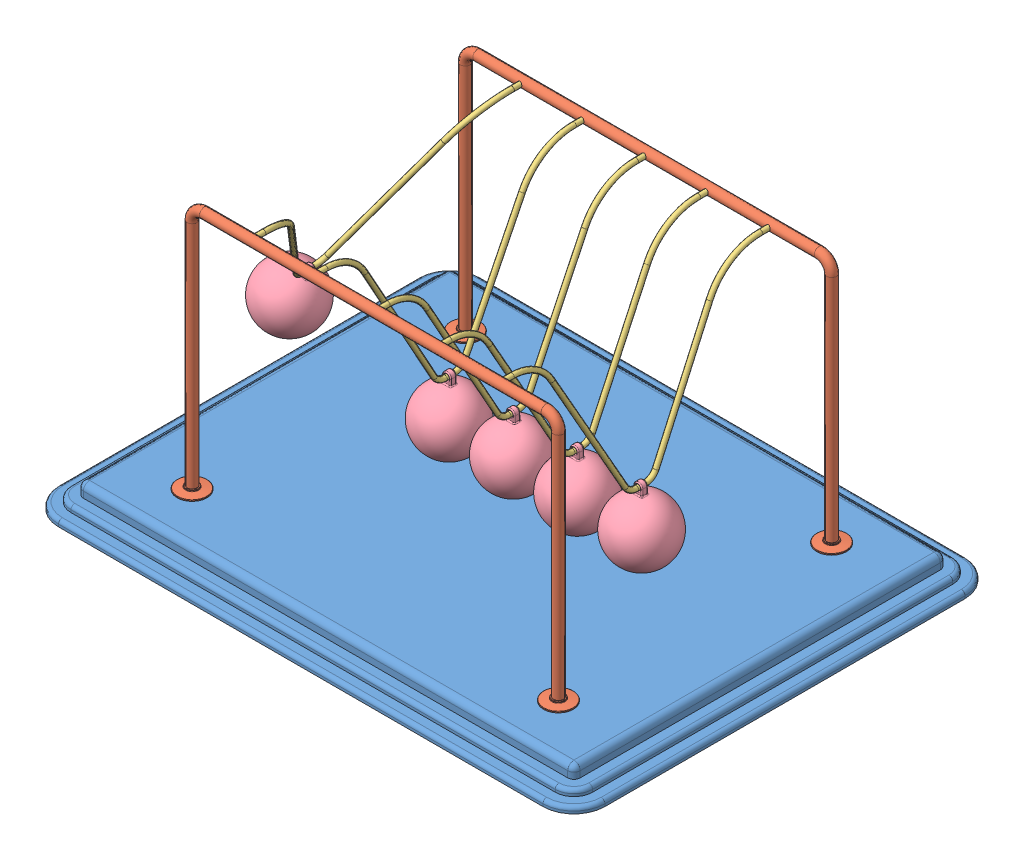
SolidWorks assembly Newtons Cradle NewtonsCradle 0243, configuration Default. Lengths in mm.
Overall size (440 222 340).
13 component instances, 4 part files, 34 mates.
Components (placement in the parent):
- Base NewtonsCradle 0243-1: Base NewtonsCradle 0243 [Default] at (-16.2968 -4.1587 11.425) size (440 20 340)
- frame NewtonsCradle 0243-1: frame NewtonsCradle 0243 [Default] at (-16.2968 144.4547 -98.575) size (319 202 24)
- frame NewtonsCradle 0243-2: frame NewtonsCradle 0243 [Default] at (-16.2968 144.4547 121.425) x (-1 0 0) z (0 0 -1) size (319 202 24)
- Hanging thing NewtonsCradle 0243-1: Hanging thing NewtonsCradle 0243 [Default] at (-157.6326 134.1825 11.425) x (0 0 1) z (-0.859985 0.510319 0) size (220 129 4)
- Hanging thing NewtonsCradle 0243-2: Hanging thing NewtonsCradle 0243 [Default] at (-66.576 122.8418 11.425) x (0 0 1) z (-0.999994 0.003446 0) size (220 129 4)
- Hanging thing NewtonsCradle 0243-3: Hanging thing NewtonsCradle 0243 [Default] at (-15.6923 122.8436 11.425) x (0 0 1) z (-0.999972 -0.007464 0) size (220 129 4)
- Hanging thing NewtonsCradle 0243-4: Hanging thing NewtonsCradle 0243 [Default] at (35.2213 122.8555 11.425) x (0 0 1) z (-0.999824 -0.018742 0) size (220 129 4)
- Hanging thing NewtonsCradle 0243-5: Hanging thing NewtonsCradle 0243 [Default] at (86.0287 122.8747 11.425) x (0 0 1) z (-0.999588 -0.028711 0) size (220 129 4)
- Sphere NewtonsCradle 0243-1: Sphere NewtonsCradle 0243 [Default] at (-195.3962 70.5436 11.425) x (0.859985 -0.510319 0) z (0 0 1) size (50 58.5 50)
- Sphere NewtonsCradle 0243-2: Sphere NewtonsCradle 0243 [Default] at (88.1533 48.9052 11.425) x (0.999588 0.028711 0) z (0 0 1) size (50 58.5 50)
- Sphere NewtonsCradle 0243-3: Sphere NewtonsCradle 0243 [Default] at (-15.14 48.8456 11.425) x (0.999972 0.007464 0) z (0 0 1) size (50 58.5 50)
- Sphere NewtonsCradle 0243-4: Sphere NewtonsCradle 0243 [Default] at (36.6081 48.8685 11.425) x (0.999824 0.018742 0) z (0 0 1) size (50 58.5 50)
- Sphere NewtonsCradle 0243-5: Sphere NewtonsCradle 0243 [Default] at (-66.831 48.8422 11.425) x (0.999994 -0.003446 0) z (0 0 1) size (50 58.5 50)
Mates (geometry in assembly coordinates):
- Coincident1: coincident anti-aligned: plane of Base-1 through (-211.2968 5.8413 156.425) normal (0 1 0); plane of frame-2 through (-175.7968 5.8413 121.425) normal (0 -1 0)
- Coincident2: coincident anti-aligned: plane of Base-1 through (-211.2968 5.8413 156.425) normal (0 1 0); plane of frame-1 through (143.2032 5.8413 -98.575) normal (0 -1 0)
- Concentric1: concentric anti-aligned: cylinder of frame-1 through (-116.2968 203.8413 -94.575) axis (0 0 -1) radius 2; cylinder of frame-2 through (-116.2968 203.8413 117.425) axis (0 0 1) radius 2
- Concentric2: concentric anti-aligned: cylinder of frame-1 through (83.7032 203.8413 -94.575) axis (0 0 -1) radius 2; cylinder of frame-2 through (83.7032 203.8413 117.425) axis (0 0 1) radius 2
- Distance1: distance = 60 mm: plane of frame-1 through (-16.2968 144.4547 -98.575) normal (0 0 1); line of Base-1 through (-211.2968 -12.1587 -158.575) axis (1 0 0)
- Distance2: distance = 60 mm: line of Base-1 through (178.7032 -12.1587 181.425) axis (-1 0 0); plane of frame-2 through (-16.2968 144.4547 121.425) normal (0 0 -1)
- Distance3: distance = 220 mm: plane of frame-2 through (-16.2968 144.4547 121.425) normal (-1 0 0); line of Base-1 through (-236.2968 -12.1587 156.425) axis (0 0 -1)
- Concentric3: concentric anti-aligned: cylinder of frame-1 through (-116.2968 203.8413 -94.575) axis (0 0 -1) radius 2; cylinder of Hanging thing-1 through (-116.2968 203.8413 111.425) axis (0 0 1) radius 2
- Concentric4: concentric anti-aligned: cylinder of frame-1 through (-116.2968 203.8413 -94.575) axis (0 0 -1) radius 2; cylinder of Hanging thing-1 through (-116.2968 203.8413 -98.575) axis (0 0 1) radius 2
- Concentric5: concentric aligned: cylinder of frame-2 through (-66.2968 203.8413 117.425) axis (0 0 1) radius 2; cylinder of Hanging thing-2 through (-66.2968 203.8413 111.425) axis (0 0 1) radius 2
- Concentric6: concentric aligned: cylinder of frame-2 through (-16.2968 203.8413 117.425) axis (0 0 1) radius 2; cylinder of Hanging thing-3 through (-16.2968 203.8413 111.425) axis (0 0 1) radius 2
- Concentric7: concentric aligned: cylinder of frame-2 through (33.7032 203.8413 117.425) axis (0 0 1) radius 2; cylinder of Hanging thing-4 through (33.7032 203.8413 111.425) axis (0 0 1) radius 2
- Concentric8: concentric aligned: cylinder of frame-2 through (83.7032 203.8413 117.425) axis (0 0 1) radius 2; cylinder of Hanging thing-5 through (83.7032 203.8413 111.425) axis (0 0 1) radius 2
- Coincident5: coincident anti-aligned: plane of frame-2 through (83.7032 203.8413 121.425) normal (0 0 -1); plane of Hanging thing-5 through (83.7032 203.8413 121.425) normal (0 0 1)
- Coincident6: coincident anti-aligned: plane of frame-2 through (33.7032 203.8413 121.425) normal (0 0 -1); plane of Hanging thing-4 through (33.7032 203.8413 121.425) normal (0 0 1)
- Coincident7: coincident anti-aligned: plane of frame-2 through (-16.2968 203.8413 121.425) normal (0 0 -1); plane of Hanging thing-3 through (-16.2968 203.8413 121.425) normal (0 0 1)
- Coincident8: coincident anti-aligned: plane of frame-2 through (-66.2968 203.8413 121.425) normal (0 0 -1); plane of Hanging thing-2 through (-66.2968 203.8413 121.425) normal (0 0 1)
- Coincident9: coincident anti-aligned: plane of frame-2 through (-116.2968 203.8413 121.425) normal (0 0 -1); plane of Hanging thing-1 through (-116.2968 203.8413 121.425) normal (0 0 1)
- Concentric9: concentric anti-aligned: cylinder of Hanging thing-1 through (-117.0163 78.8434 7.925) axis (0 0 1) radius 2; cylinder of Sphere-1 through (-117.0163 78.8434 13.925) axis (0 0 -1) radius 2
- Concentric13: concentric anti-aligned: cylinder of Hanging thing-2 through (-66.7276 78.842 7.925) axis (0 0 1) radius 2; cylinder of Sphere-5 through (-66.7276 78.842 13.925) axis (0 0 -1) radius 2
- Concentric15: concentric anti-aligned: cylinder of Hanging thing-3 through (-15.3639 78.8448 7.925) axis (0 0 1) radius 2; cylinder of Sphere-3 through (-15.3639 78.8448 13.925) axis (0 0 -1) radius 2
- Concentric16: concentric anti-aligned: cylinder of Hanging thing-5 through (87.292 78.8928 7.925) axis (0 0 1) radius 2; cylinder of Sphere-2 through (87.292 78.8928 13.925) axis (0 0 -1) radius 2
- Concentric17: concentric anti-aligned: cylinder of Hanging thing-4 through (36.0459 78.8632 7.925) axis (0 0 1) radius 2; cylinder of Sphere-4 through (36.0459 78.8632 13.925) axis (0 0 -1) radius 2
- Parallel1: parallel anti-aligned: plane of Hanging thing-1; plane of Sphere-1
- Coincident22: coincident anti-aligned: plane of Hanging thing-1; plane of Sphere-1
- Coincident12: coincident aligned: plane of Hanging thing-2 through (-66.576 122.8418 11.425) normal (0 0 1); plane of Sphere-5 through (-66.831 48.8422 11.425) normal (0 0 1)
- Coincident10: coincident aligned: plane of Hanging thing-1 through (-116.763 122.8426 11.425) normal (0 0 1); plane of Sphere-1 through (-118.5806 48.8842 11.425) normal (0 0 1)
- Coincident13: coincident anti-aligned: plane of Hanging thing-2 through (-66.576 122.8418 11.425) normal (-0.999994 0.003446 0); plane of Sphere-5 through (-66.831 48.8422 11.425) normal (0.999994 -0.003446 0)
- Coincident14: coincident anti-aligned: plane of Hanging thing-3 through (-15.6923 122.8436 11.425) normal (-0.999972 -0.007464 0); plane of Sphere-3 through (-15.14 48.8456 11.425) normal (0.999972 0.007464 0)
- Coincident15: coincident aligned: plane of Hanging thing-3 through (-15.6923 122.8436 11.425) normal (0 0 1); plane of Sphere-3 through (-15.14 48.8456 11.425) normal (0 0 1)
- Coincident18: coincident aligned: plane of Hanging thing-4 through (35.2213 122.8555 11.425) normal (0 0 1); plane of Sphere-4 through (36.6081 48.8685 11.425) normal (0 0 1)
- Coincident19: coincident anti-aligned: plane of Hanging thing-4 through (35.2213 122.8555 11.425) normal (-0.999824 -0.018742 0); plane of Sphere-4 through (36.6081 48.8685 11.425) normal (0.999824 0.018742 0)
- Coincident20: coincident anti-aligned: plane of Hanging thing-5 through (86.0287 122.8747 11.425) normal (-0.999588 -0.028711 0); plane of Sphere-2 through (88.1533 48.9052 11.425) normal (0.999588 0.028711 0)
- Coincident21: coincident aligned: plane of Hanging thing-5 through (86.0287 122.8747 11.425) normal (0 0 1); plane of Sphere-2 through (88.1533 48.9052 11.425) normal (0 0 1)
